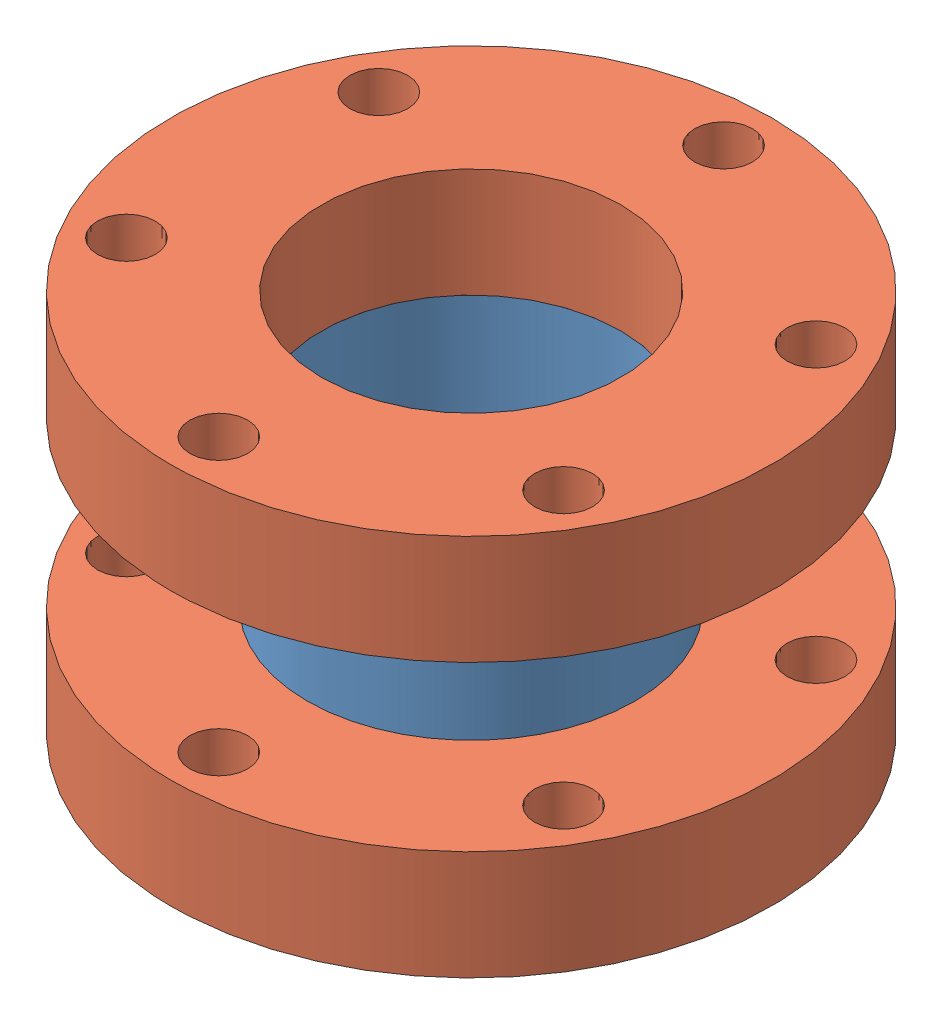
SolidWorks assembly minilength_nipple, configuration Default. Lengths in mm.
Overall size (69.85 44.45 69.85).
3 component instances, 2 part files, 3 mates.
Components (placement in the parent):
- minilength_nipple_tube-1: minilength_nipple_tube [Default] at (-7.6879 4.7765 0.8117) size (38.1 19.05 38.1)
- 2.75in_CF_flange-3: 2.75in_CF_flange [Default] at (-7.6879 14.3015 0.8117) size (69.85 12.7 69.85)
- 2.75in_CF_flange-4: 2.75in_CF_flange [Default] at (-7.6879 -17.4485 0.8117) size (69.85 12.7 69.85)
Mates (geometry in assembly coordinates):
- Coincident1: coincident aligned: circle of minilength_nipple_tube-1; circle of 2.75in_CF_flange-3
- Coincident2: coincident aligned: circle of minilength_nipple_tube-1; circle of 2.75in_CF_flange-4
- Parallel1: parallel aligned: line of 2.75in_CF_flange-3 through (-7.6879 14.3015 0.8117) axis (0 0 -1); line of 2.75in_CF_flange-4 through (-7.6879 -17.4485 0.8117) axis (0 0 -1)
